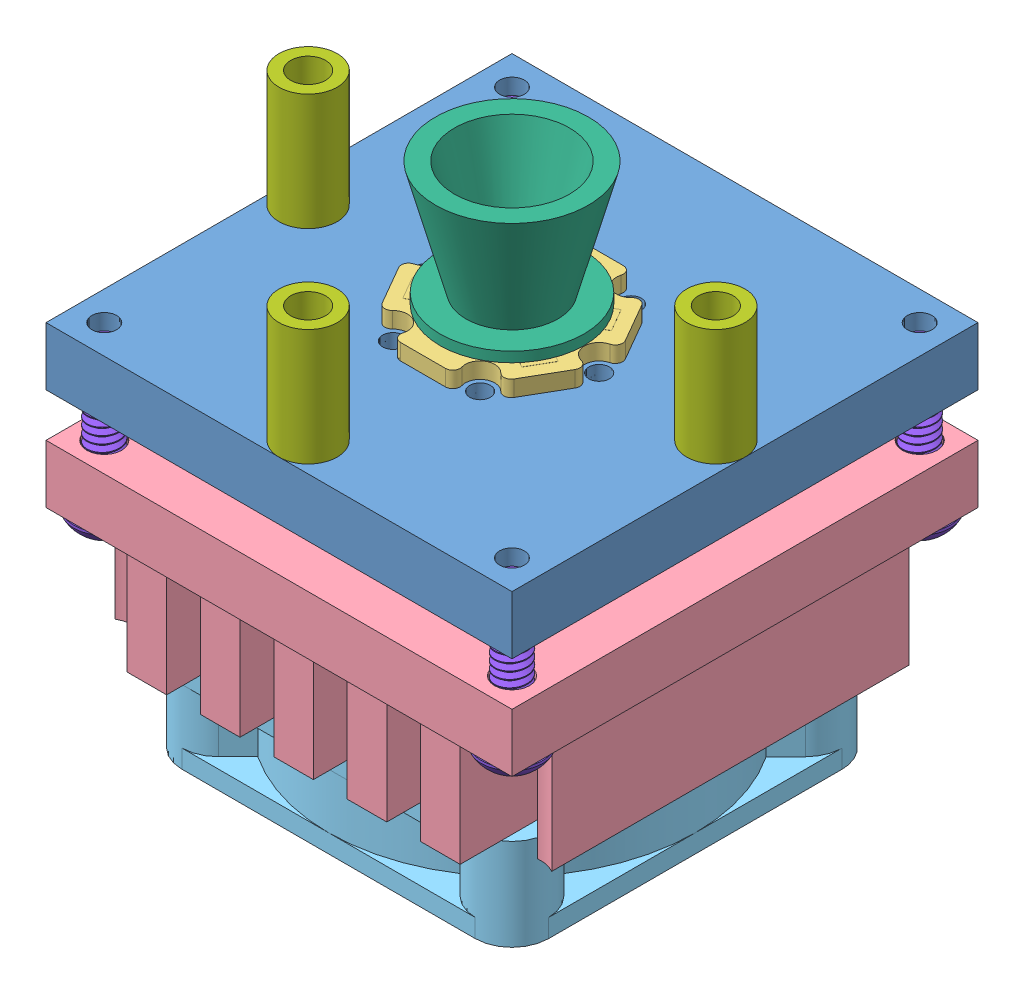
SolidWorks assembly Retina Fucker, configuration Default. Lengths in mm.
Overall size (51.1 57 52.54).
17 component instances, 9 part files, 36 mates.
Components (placement in the parent):
- LED Interface Plate-1: LED Interface Plate [Default] at (13.1908 22.1092 31.2346) size (50.8 6.35 52.39)
- Peltier Junction-1: Peltier Junction [Default] at (13.1908 17.3467 31.2346) size (39.69 4.76 39.69)
- LZ4-40G108-0000-1: LZ4-40G108-0000 [Default] at (13.1908 28.4592 31.2346) size (19.46 5.4 19.4)
- Heatsink-1: Heatsink [Default] at (13.1948 17.3467 31.2346) x (0 0 -1) z (-1 0 0) size (50.8 19.05 50.8)
- 1939K170_DC EQUIPMENT COOLING FAN-1: 1939K170_DC EQUIPMENT COOLING FAN [Default] at (13.1908 -1.7033 31.2346) x (-0.000125 0 1) z (0 -1 0) size (40 40 10.64)
- Reflector-1: Reflector [Default] at (13.1908 30.2092 31.2346) x (0.991681 0 -0.128723) z (0.128723 0 0.991681) size (16.67 13.5 16.67)
- Front Mounting Spacer-1: Front Mounting Spacer [Default] at (-9.0342 28.4592 31.2346) x (1 0 0) z (0 1 0) size (6.35 6.35 12.7)
- Front Mounting Spacer-2: Front Mounting Spacer [Default] at (13.1908 28.4592 53.4596) x (1 0 0) z (0 1 0) size (6.35 6.35 12.7)
- Front Mounting Spacer-3: Front Mounting Spacer [Default] at (35.4158 28.4592 31.2346) x (1 0 0) z (0 1 0) size (6.35 6.35 12.7)
- 91255A150_ALLOY STEEL BUTTON-HEAD SOCKET CAP SCREW 6-32 5_8-1: 91255A150_ALLOY STEEL BUTTON-HEAD SOCKET CAP SCREW 6-32 5_8 [91255A150] at (-9.0302 9.1425 9.0096) x (1 0 0) z (0 -1 0) size (6.65 6.65 18.16)
- 91255A150_ALLOY STEEL BUTTON-HEAD SOCKET CAP SCREW 6-32 5_8-2: 91255A150_ALLOY STEEL BUTTON-HEAD SOCKET CAP SCREW 6-32 5_8 [91255A150] at (-9.0302 9.1425 53.4596) x (1 0 0) z (0 -1 0) size (6.65 6.65 18.16)
- 91255A150_ALLOY STEEL BUTTON-HEAD SOCKET CAP SCREW 6-32 5_8-3: 91255A150_ALLOY STEEL BUTTON-HEAD SOCKET CAP SCREW 6-32 5_8 [91255A150] at (35.4198 9.1425 53.4596) x (1 0 0) z (0 -1 0) size (6.65 6.65 18.16)
- 91255A150_ALLOY STEEL BUTTON-HEAD SOCKET CAP SCREW 6-32 5_8-4: 91255A150_ALLOY STEEL BUTTON-HEAD SOCKET CAP SCREW 6-32 5_8 [91255A150] at (35.4198 9.1425 9.0096) x (1 0 0) z (0 -1 0) size (6.65 6.65 18.16)
- 91255A110_ALLOY STEEL BUTTON-HEAD SOCKET CAP SCREW 4-40 1_2-1: 91255A110_ALLOY STEEL BUTTON-HEAD SOCKET CAP SCREW 4-40 1_2 [91255A110] at (29.1928 -13.2019 15.2366) x (1 0 0) z (0 -1 0) size (5.41 5.41 14.54)
- 91255A110_ALLOY STEEL BUTTON-HEAD SOCKET CAP SCREW 4-40 1_2-2: 91255A110_ALLOY STEEL BUTTON-HEAD SOCKET CAP SCREW 4-40 1_2 [91255A110] at (-2.8072 -13.2019 15.2326) x (1 0 0) z (0 -1 0) size (5.41 5.41 14.54)
- 91255A110_ALLOY STEEL BUTTON-HEAD SOCKET CAP SCREW 4-40 1_2-3: 91255A110_ALLOY STEEL BUTTON-HEAD SOCKET CAP SCREW 4-40 1_2 [91255A110] at (29.1888 -13.2019 47.2366) x (1 0 0) z (0 -1 0) size (5.41 5.41 14.54)
- 91255A110_ALLOY STEEL BUTTON-HEAD SOCKET CAP SCREW 4-40 1_2-4: 91255A110_ALLOY STEEL BUTTON-HEAD SOCKET CAP SCREW 4-40 1_2 [91255A110] at (-2.8112 -13.2019 47.2326) x (1 0 0) z (0 -1 0) size (5.41 5.41 14.54)
Mates (geometry in assembly coordinates):
- Coincident1: coincident anti-aligned: plane of LED Interface Plate-1 through (13.1908 28.4592 31.2346) normal (0 1 0); plane of LZ4-40G108-0000-1 through (13.1908 28.4592 31.2346) normal (0 -1 0)
- Concentric1: concentric aligned: cylinder of LED Interface Plate-1 through (17.9408 28.4592 39.4619) axis (0 1 0) radius 1.1303; cylinder of LZ4-40G108-0000-1 through (17.9408 28.4592 39.4619) axis (0 1 0) radius 1.6
- Concentric2: concentric aligned: cylinder of LED Interface Plate-1 through (8.4408 28.4592 39.4619) axis (0 1 0) radius 1.1303; cylinder of LZ4-40G108-0000-1 through (8.4408 28.4592 39.4619) axis (0 1 0) radius 1.6
- Coincident2: coincident anti-aligned: plane of LED Interface Plate-1 through (13.1908 22.1092 31.2346) normal (0 -1 0); plane of Peltier Junction-1 through (13.1908 22.1092 31.2346) normal (0 1 0)
- Coincident3: coincident aligned: plane of LED Interface Plate-1 through (13.1908 22.1092 31.2346) normal (0 0 1); plane of Peltier Junction-1 through (13.1908 17.3467 31.2346) normal (0 0 1)
- Coincident4: coincident aligned: plane of LED Interface Plate-1 through (13.1908 22.1092 31.2346) normal (1 0 0); plane of Peltier Junction-1 through (13.1908 17.3467 31.2346) normal (1 0 0)
- Coincident5: coincident anti-aligned: plane of Peltier Junction-1 through (13.1908 17.3467 31.2346) normal (0 -1 0); plane of Heatsink-1 through (13.1948 17.3467 31.2346) normal (0 1 0)
- Coincident6: coincident anti-aligned: plane of Heatsink-1 through (-9.0302 -1.7033 53.4596) normal (0 -1 0); plane of 1939K170_DC EQUIPMENT COOLING FAN-1 through (29.1888 -1.7033 47.2366) normal (0 1 0)
- Parallel1: parallel aligned: plane of Heatsink-1 through (-12.2052 10.9967 5.8346) normal (0 0 -1); plane of LED Interface Plate-1 through (38.5908 28.4592 5.8346) normal (0 0 -1)
- Coincident9: coincident aligned: line of LED Interface Plate-1 through (13.1908 22.1092 31.2346) axis (0 -1 0); axis of 1939K170_DC EQUIPMENT COOLING FAN-1 through (13.1908 -3.7033 31.2346) axis (0 -1 0)
- Concentric5: concentric anti-aligned: cylinder of Heatsink-1 through (-2.8072 -1.7033 15.2326) axis (0 -1 0) radius 1.1303; cylinder of 1939K170_DC EQUIPMENT COOLING FAN-1 through (-2.8072 -11.7033 15.2326) axis (0 1 0) radius 1.778
- Concentric9: concentric aligned: circle of LZ4-40G108-0000-1; axis of Reflector-1 through (13.1908 43.7092 31.2346) axis (0 -1 0)
- Coincident12: coincident anti-aligned: plane of LZ4-40G108-0000-1 through (13.1908 30.2092 31.2346) normal (0 1 0); plane of Reflector-1 through (17.3261 30.2092 30.6978) normal (0 -1 0)
- Coincident13: coincident anti-aligned: plane of LED Interface Plate-1 through (13.1908 28.4592 31.2346) normal (0 1 0); plane of Front Mounting Spacer-3 through (35.4158 28.4592 31.2346) normal (0 -1 0)
- Coincident14: coincident anti-aligned: plane of LED Interface Plate-1 through (13.1908 28.4592 31.2346) normal (0 1 0); plane of Front Mounting Spacer-2 through (13.1908 28.4592 53.4596) normal (0 -1 0)
- Coincident15: coincident anti-aligned: plane of LED Interface Plate-1 through (13.1908 28.4592 31.2346) normal (0 1 0); plane of Front Mounting Spacer-1 through (-9.0342 28.4592 31.2346) normal (0 -1 0)
- Concentric10: concentric anti-aligned: circle of LED Interface Plate-1; cylinder of Front Mounting Spacer-1 through (-9.0342 41.1592 31.2346) axis (0 -1 0) radius 3.175
- Concentric11: concentric anti-aligned: circle of LED Interface Plate-1; cylinder of Front Mounting Spacer-2 through (13.1908 41.1592 53.4596) axis (0 -1 0) radius 3.175
- Concentric12: concentric anti-aligned: cylinder of LED Interface Plate-1 through (35.4158 28.4592 31.2346) axis (0 1 0) radius 1.3526; cylinder of Front Mounting Spacer-3 through (35.4158 41.1592 31.2346) axis (0 -1 0) radius 3.175
- Coincident16: coincident aligned: plane of LED Interface Plate-1 through (38.5908 28.4592 5.8346) normal (0 0 -1); plane of Heatsink-1 through (-12.2052 10.9967 5.8346) normal (0 0 -1)
- Coincident17: coincident anti-aligned: plane of Heatsink-1 through (13.1948 10.9967 31.2346) normal (0 -1 0); plane of 91255A150_ALLOY STEEL BUTTON-HEAD SOCKET CAP SCREW 6-32 5_8-1 through (-9.0302 10.9967 5.6822) normal (0 1 0)
- Coincident18: coincident anti-aligned: plane of Heatsink-1 through (13.1948 10.9967 31.2346) normal (0 -1 0); plane of 91255A150_ALLOY STEEL BUTTON-HEAD SOCKET CAP SCREW 6-32 5_8-2 through (-9.0302 10.9967 50.1322) normal (0 1 0)
- Coincident19: coincident anti-aligned: plane of Heatsink-1 through (13.1948 10.9967 31.2346) normal (0 -1 0); plane of 91255A150_ALLOY STEEL BUTTON-HEAD SOCKET CAP SCREW 6-32 5_8-3 through (35.4198 10.9967 50.1322) normal (0 1 0)
- Coincident20: coincident anti-aligned: plane of Heatsink-1 through (13.1948 10.9967 31.2346) normal (0 -1 0); plane of 91255A150_ALLOY STEEL BUTTON-HEAD SOCKET CAP SCREW 6-32 5_8-4 through (35.4198 10.9967 5.6822) normal (0 1 0)
- Concentric13: concentric aligned: cylinder of Heatsink-1 through (-9.0302 10.9967 9.0096) axis (0 -1 0) radius 1.8986; circle of 91255A150_ALLOY STEEL BUTTON-HEAD SOCKET CAP SCREW 6-32 5_8-1
- Concentric14: concentric aligned: cylinder of Heatsink-1 through (-9.0302 10.9967 53.4596) axis (0 -1 0) radius 1.8986; circle of 91255A150_ALLOY STEEL BUTTON-HEAD SOCKET CAP SCREW 6-32 5_8-2
- Concentric15: concentric aligned: cylinder of Heatsink-1 through (35.4198 10.9967 53.4596) axis (0 -1 0) radius 1.8986; circle of 91255A150_ALLOY STEEL BUTTON-HEAD SOCKET CAP SCREW 6-32 5_8-3
- Concentric16: concentric aligned: circle of Heatsink-1; circle of 91255A150_ALLOY STEEL BUTTON-HEAD SOCKET CAP SCREW 6-32 5_8-4
- Coincident21: coincident anti-aligned: plane of 1939K170_DC EQUIPMENT COOLING FAN-1 through (13.1908 -11.7033 31.2346) normal (0 -1 0); plane of 91255A110_ALLOY STEEL BUTTON-HEAD SOCKET CAP SCREW 4-40 1_2-1 through (29.1928 -11.7033 12.5315) normal (0 1 0)
- Coincident22: coincident anti-aligned: plane of 1939K170_DC EQUIPMENT COOLING FAN-1 through (13.1908 -11.7033 31.2346) normal (0 -1 0); plane of 91255A110_ALLOY STEEL BUTTON-HEAD SOCKET CAP SCREW 4-40 1_2-2 through (-2.8072 -11.7033 12.5275) normal (0 1 0)
- Coincident23: coincident anti-aligned: plane of 1939K170_DC EQUIPMENT COOLING FAN-1 through (13.1908 -11.7033 31.2346) normal (0 -1 0); plane of 91255A110_ALLOY STEEL BUTTON-HEAD SOCKET CAP SCREW 4-40 1_2-3 through (29.1888 -11.7033 44.5315) normal (0 1 0)
- Coincident24: coincident anti-aligned: plane of 1939K170_DC EQUIPMENT COOLING FAN-1 through (13.1908 -11.7033 31.2346) normal (0 -1 0); plane of 91255A110_ALLOY STEEL BUTTON-HEAD SOCKET CAP SCREW 4-40 1_2-4 through (-2.8112 -11.7033 44.5275) normal (0 1 0)
- Concentric17: concentric anti-aligned: cylinder of 1939K170_DC EQUIPMENT COOLING FAN-1 through (29.1928 -11.7033 15.2366) axis (0 1 0) radius 1.778; circle of 91255A110_ALLOY STEEL BUTTON-HEAD SOCKET CAP SCREW 4-40 1_2-1
- Concentric18: concentric anti-aligned: cylinder of 1939K170_DC EQUIPMENT COOLING FAN-1 through (-2.8072 -11.7033 15.2326) axis (0 1 0) radius 1.778; circle of 91255A110_ALLOY STEEL BUTTON-HEAD SOCKET CAP SCREW 4-40 1_2-2
- Concentric19: concentric anti-aligned: cylinder of 1939K170_DC EQUIPMENT COOLING FAN-1 through (29.1888 -11.7033 47.2366) axis (0 1 0) radius 1.778; circle of 91255A110_ALLOY STEEL BUTTON-HEAD SOCKET CAP SCREW 4-40 1_2-3
- Concentric20: concentric anti-aligned: cylinder of 1939K170_DC EQUIPMENT COOLING FAN-1 through (-2.8112 -11.7033 47.2326) axis (0 1 0) radius 1.778; circle of 91255A110_ALLOY STEEL BUTTON-HEAD SOCKET CAP SCREW 4-40 1_2-4
